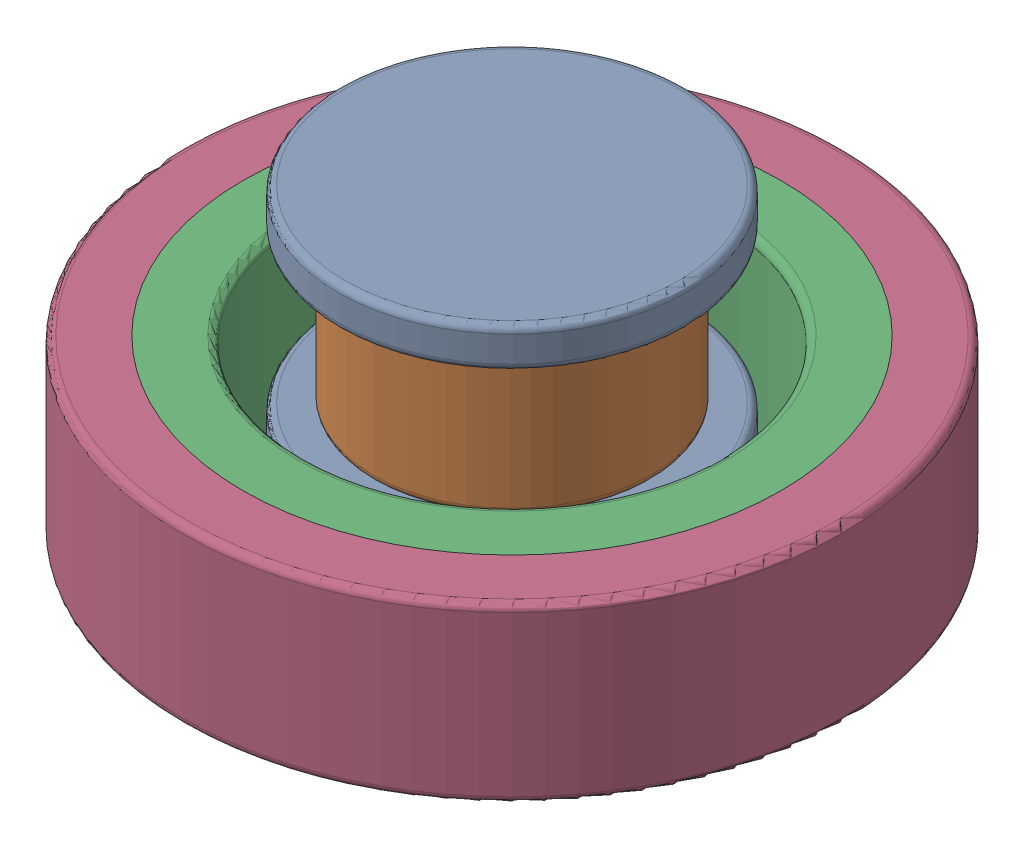
SolidWorks assembly MagneticCircuit, configuration Default. Lengths in mm.
Overall size (19 8.77 19).
4 component instances, 4 part files, 15 mates.
Components (placement in the parent):
- Core-1: Core [Default] at (0 -5.45 0) x (0.999989 0 -0.004774) z (0.004774 0 0.999989) size (10 6.6 10)
- Coil-1: Coil [Default] at (0 -4.3 0) size (8 4.3 8)
- MovingMass6_Inner-1: MovingMass6_Inner [Default] at (0 -7.6173 0) size (15.5 5 15.5)
- MovingMass6_Outer-1: MovingMass6_Outer [Default] at (0 -7.6173 0) size (19 5 19)
Mates (geometry in assembly coordinates):
- Coincident1: coincident anti-aligned: cylinder of Core-1 through (0 0 0) axis (0 -1 0) radius 2.4; circle of Coil-1
- Coincident2: coincident anti-aligned: plane of Core-1 through (0 -4.3 0) normal (0 1 0); plane of Coil-1 through (0 -4.3 0) normal (0 -1 0)
- Concentric1: concentric aligned: circle of Core-1; circle of MovingMass1-1
- Coincident6: coincident: point of Core-1; point of assembly
- Parallel1: parallel aligned: plane of Core-1 through (0 1.15 0) normal (0 1 0)
- Concentric2: concentric aligned: circle of Core-1; circle of MovingMass2-1
- Coincident8: coincident anti-aligned: plane of MovingMass3_Bottom-1 through (0 -8.7273 0) normal (0 1 0); plane of MovingMass3_Top-1 through (0 -8.7273 0) normal (0 -1 0)
- Coincident9: coincident aligned: circle of MovingMass3_Bottom-1; circle of MovingMass3_Top-1
- Concentric3: concentric anti-aligned: circle of Core-1; circle of MovingMass3_Top-1
- Coincident10: coincident anti-aligned: plane of MovingMass4_Bottom-1 through (0 -5.2306 0) normal (0 1 0); plane of MovingMass4_Top-1 through (0 -5.2306 0) normal (0 -1 0)
- Concentric4: concentric aligned: circle of MovingMass4_Bottom-1; circle of MovingMass4_Top-1
- Concentric5: concentric anti-aligned: circle of Core-1; circle of MovingMass4_Top-1
- Coincident16: coincident aligned: plane of MovingMass6_Inner-1 through (0 -2.6173 0) normal (0 1 0); plane of MovingMass6_Outer-1 through (0 -2.6173 0) normal (0 1 0)
- Concentric10: concentric anti-aligned: circle of MovingMass6_Inner-1; circle of MovingMass6_Outer-1
- Concentric11: concentric aligned: circle of Core-1; circle of MovingMass6_Outer-1
